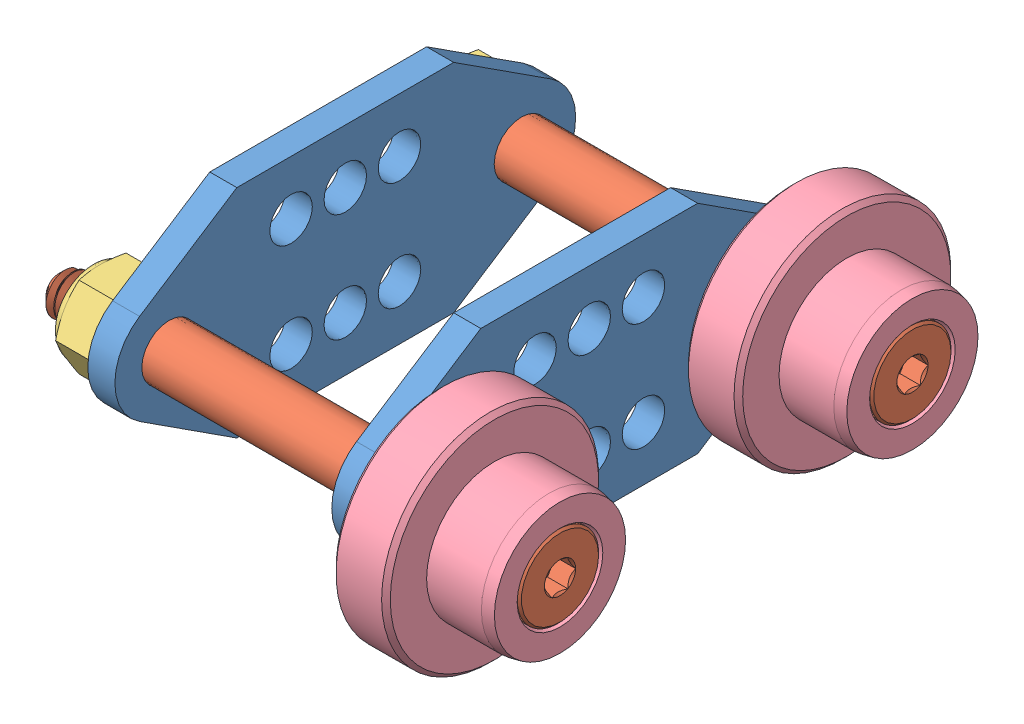
SolidWorks assembly CRP_E_002, configuration Default. Lengths in mm.
Overall size (58.92 25.4 66.67).
8 component instances, 4 part files, 0 mates.
Components (placement in the parent):
- CRP_ELE_V2_003-1: CRP_ELE_V2_003 [Default] x (0 0 -1) z (1 0 0) size (53.98 25.4 3.18)
- CRP_ELE_V2_003-2: CRP_ELE_V2_003 [Default] at (-28.575 0 0) x (0 0 -1) z (1 0 0) size (53.98 25.4 3.18)
- Shoulder_Screw_.25dia_1.75long_10-24_91259A102-1: Shoulder_Screw_.25dia_1.75long_10-24_91259A102 [Default] at (15.621 0 20.6375) x (0 -1 0) z (0 0 1) size (9.53 58.92 9.53)
- Shoulder_Screw_.25dia_1.75long_10-24_91259A102-2: Shoulder_Screw_.25dia_1.75long_10-24_91259A102 [Default] at (15.621 0 -20.6375) x (0 -1 0) z (0 0 1) size (9.53 58.92 9.53)
- Nut_Nylock_10-24_ZP_90631A011-1: Nut_Nylock_10-24_ZP_90631A011 [Default] at (-28.575 0 20.6375) x (0 1 0) z (0 0 1) size (9.53 6.11 11)
- Nut_Nylock_10-24_ZP_90631A011-2: Nut_Nylock_10-24_ZP_90631A011 [Default] at (-28.575 0 -20.6375) x (0 1 0) z (0 0 1) size (9.53 6.11 11)
- CRP_ELE_V2_001-1: CRP_ELE_V2_001 [Default] at (3.175 0 20.6375) size (17.21 25.4 25.4)
- CRP_ELE_V2_001-2: CRP_ELE_V2_001 [Default] at (3.175 0 -20.6375) size (17.21 25.4 25.4)
